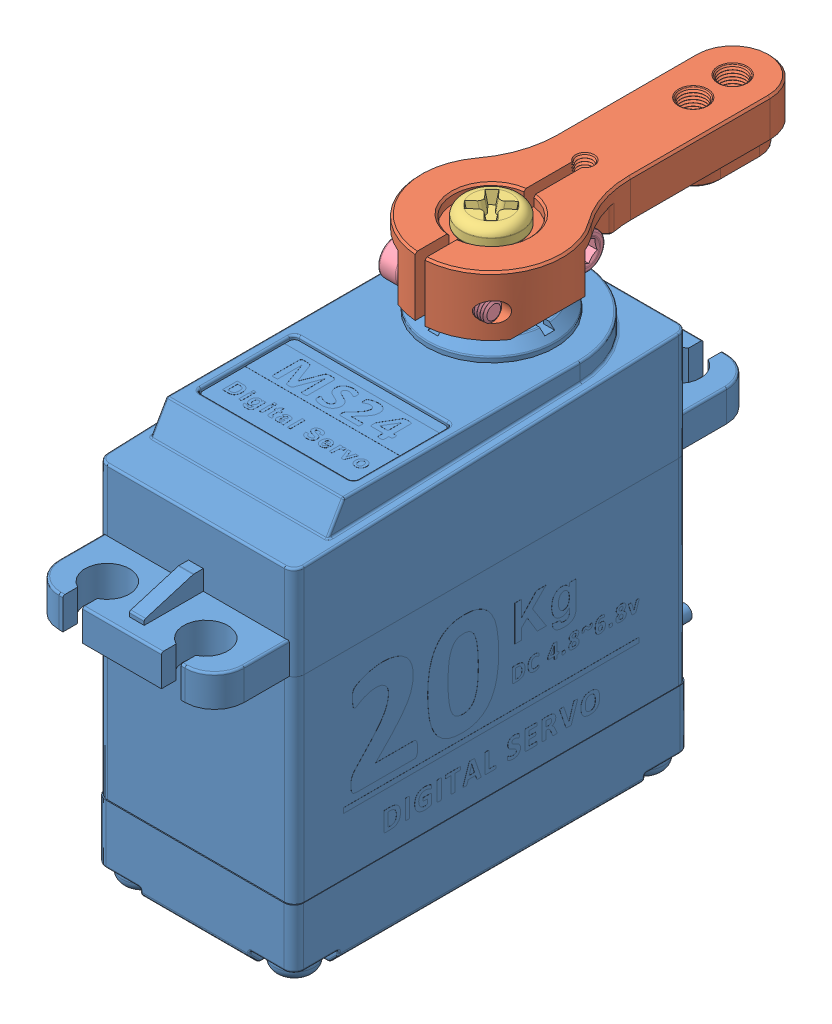
SolidWorks assembly DIGITAL SERVO ASSEMBLY, configuration Default. Lengths in mm.
Overall size (20.1 49.37 65.8).
5 component instances, 4 part files, 11 mates.
Components (placement in the parent):
- DS3218MG MS24 Digital Servo 270-1: DS3218MG MS24 Digital Servo 270 [Default] at origin size (20.1 45.99 55.6)
- Servo Arm for DS3218MG-1: Servo Arm for DS3218MG [Default] at (0 21 0) x (-1 0 0) z (0 0 -1) size (14.5 6.15 35.53)
- Screw-01 for DS3218MG-1: Screw-01 for DS3218MG [Default] at (0 20 0) x (0.722727 0 -0.691134) z (0.691134 0 0.722727) size (6 6.6 6)
- Screw-02 for DS3218MG-2: Screw-02 for DS3218MG [Default] at (-2.75 17.5 5) x (0 0.939517 0.342502) z (0 -0.342502 0.939517) size (3.6 10.03 3.6)
- Screw-02 for DS3218MG-3: Screw-02 for DS3218MG [Default] at (2.75 17.5 -5) x (0 -0.201856 0.979415) z (0 0.979415 0.201856) size (3.6 10.03 3.6)
Mates (geometry in assembly coordinates):
- Concentric1: concentric anti-aligned: cylinder of DS3218MG MS24 Digital Servo 270-1 through (0 14.4 0) axis (0 1 0) radius 1.25; cylinder of Servo Arm for DS3218MG-1 through (0 18.4 0) axis (0 -1 0) radius 2.5
- Coincident1: coincident anti-aligned: plane of DS3218MG MS24 Digital Servo 270-1 through (0 18.4 0) normal (0 1 0); plane of Servo Arm for DS3218MG-1 through (0 18.4 0) normal (0 -1 0)
- LimitAngle1: limit planar angle = 3.141593 rad aligned: plane of Servo Arm for DS3218MG-1 through (3.8 15 -24.5) normal (1 0 0); plane of DS3218MG MS24 Digital Servo 270-1 through (-10 11 -9) normal (-1 0 0)
- Concentric2: concentric aligned: cylinder of Servo Arm for DS3218MG-1 through (0 15 0) axis (0 1 0) radius 1.5; cylinder of Screw-01 for DS3218MG-1 through (0 21.8 0) axis (0 1 0) radius 1.45
- Coincident2: coincident anti-aligned: plane of Servo Arm for DS3218MG-1 through (0 20 0) normal (0 1 0); plane of Screw-01 for DS3218MG-1 through (1.048 20 -1.0021) normal (0 -1 0)
- Concentric3: concentric aligned: cylinder of Servo Arm for DS3218MG-1 through (0 15 -24.5) axis (0 1 0) radius 1.25; cylinder of Screw-02 for DS3218MG-1 through (0 24.245 -24.5) axis (0 1 0) radius 0.95
- Concentric4: concentric aligned: cylinder of Servo Arm for DS3218MG-1 through (7.25 17.5 5) axis (-1 0 0) radius 0.75; cylinder of Screw-02 for DS3218MG-2 through (-4.75 17.5 5) axis (-1 0 0) radius 0.95
- Parallel1: parallel aligned: plane of DS3218MG MS24 Digital Servo 270-1 through (-10 11 -9) normal (-1 0 0); plane of Servo Arm for DS3218MG-1 through (-3.8 15 -24.5) normal (-1 0 0)
- Coincident3: coincident anti-aligned: plane of Servo Arm for DS3218MG-1 through (-2.75 32.1097 4.5) normal (-1 0 0); plane of Screw-02 for DS3218MG-2 through (-2.75 19.0032 5.548) normal (1 0 0)
- Concentric5: concentric anti-aligned: cylinder of Servo Arm for DS3218MG-1 through (7.25 17.5 -5) axis (-1 0 0) radius 0.75; cylinder of Screw-02 for DS3218MG-3 through (4.75 17.5 -5) axis (1 0 0) radius 1.8
- Coincident4: coincident anti-aligned: plane of Servo Arm for DS3218MG-1 through (2.75 32.1097 -6.7622) normal (1 0 0); plane of Screw-02 for DS3218MG-3 through (2.75 17.177 -3.4329) normal (-1 0 0)
